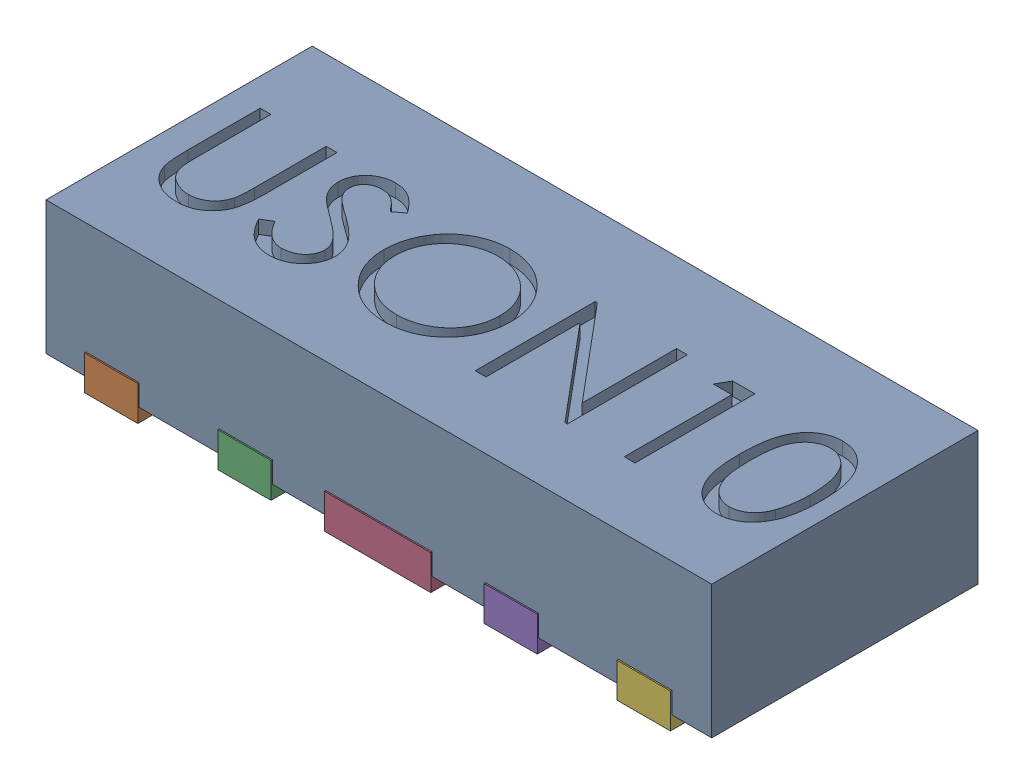
SolidWorks assembly UDFN10, configuration Défaut. Lengths in mm.
Overall size (2.5 0.55 1.01).
11 component instances, 5 part files, 0 mates.
Components (placement in the parent):
- User Library-UDFN10_Body-1: User Library-UDFN10_Body [Défaut] at (1.0785 0.9721 1.8983) size (2.5 0.5 1)
- User Library-UDFN10_Pin1-1: User Library-UDFN10_Pin1 [Défaut] at (0.0785 1.0521 2.2208) x (0 0 -1) z (-1 0 0) size (0.37 0.13 0.2)
- User Library-UDFN10_Pin2-1: User Library-UDFN10_Pin2 [Défaut] at (0.5785 1.0521 2.2208) x (0 0 1) z (1 0 0) size (0.37 0.13 0.2)
- User Library-UDFN10_Pin4-1: User Library-UDFN10_Pin4 [Défaut] at (1.0785 0.9221 2.2208) x (0 0 1) z (-1 0 0) size (0.49 0.13 0.4)
- User Library-UDFN10_Pin2-2: User Library-UDFN10_Pin2 [Défaut] at (1.5785 0.9221 2.2208) x (0 0 1) z (-1 0 0) size (0.37 0.13 0.2)
- User Library-UDFN10_Pin2-3: User Library-UDFN10_Pin2 [Défaut] at (2.0785 0.9221 2.2208) x (0 0 1) z (-1 0 0) size (0.37 0.13 0.2)
- User Library-UDFN10_Pin2-4: User Library-UDFN10_Pin2 [Défaut] at (2.0785 0.9221 1.5758) x (0 0 -1) z (1 0 0) size (0.37 0.13 0.2)
- User Library-UDFN10_Pin2-5: User Library-UDFN10_Pin2 [Défaut] at (1.5785 0.9221 1.5758) x (0 0 -1) z (1 0 0) size (0.37 0.13 0.2)
- User Library-UDFN10_Pin3-1: User Library-UDFN10_Pin3 [Défaut] at (1.0785 0.9221 1.5758) x (0 0 1) z (-1 0 0) size (0.37 0.13 0.4)
- User Library-UDFN10_Pin2-6: User Library-UDFN10_Pin2 [Défaut] at (0.5785 0.9221 1.5758) x (0 0 -1) z (1 0 0) size (0.37 0.13 0.2)
- User Library-UDFN10_Pin2-7: User Library-UDFN10_Pin2 [Défaut] at (0.0785 0.9221 1.5758) x (0 0 -1) z (1 0 0) size (0.37 0.13 0.2)
